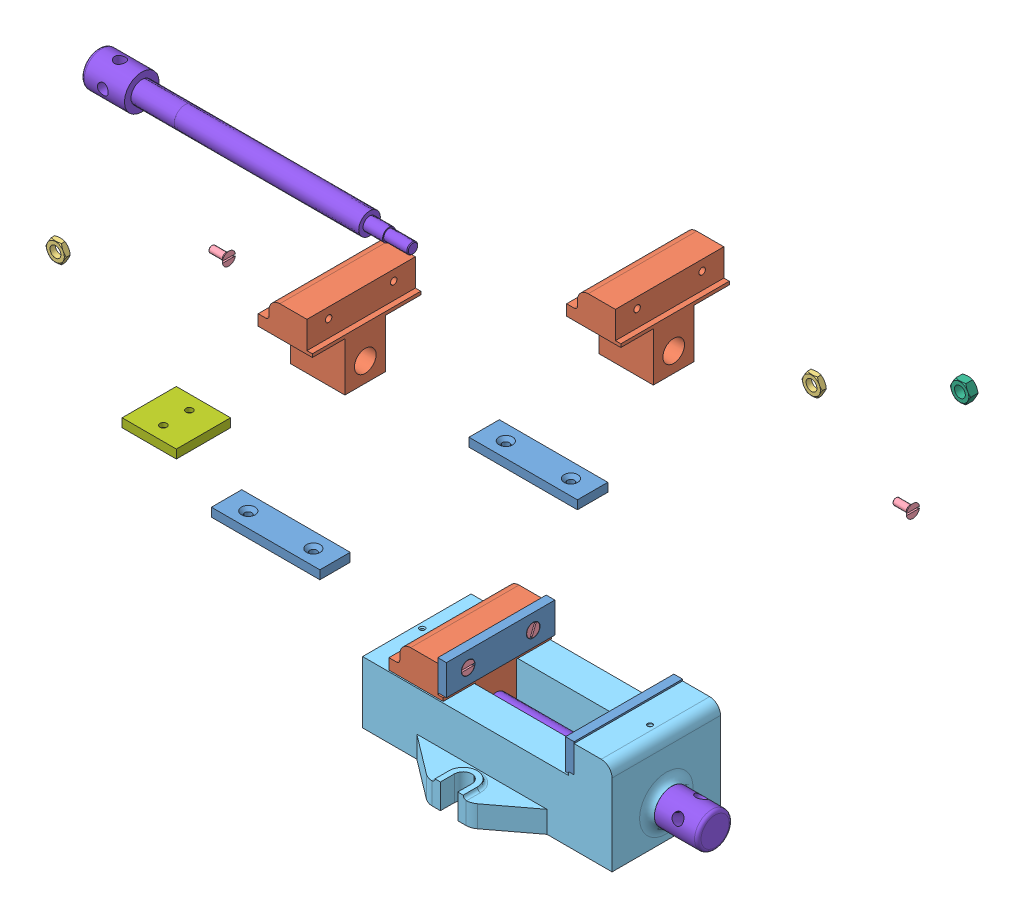
SolidWorks assembly Assem1, configuration Default. Lengths in mm.
Overall size (595.96 344.62 324.17).
26 component instances, 8 part files, 0 mates.
Components (placement in the parent):
- Grip-MV-1: Grip-MV [Default] at (31.9999 68.4692 65.7892) size (100 8 28)
- Jaw-MV-1: Jaw-MV [Default] at (-133.3209 133.664 48.2001) size (50 73 100)
- Lock NUt-MV-1: Lock NUt-MV [Default] at (173.2845 151.3233 -49.7428) size (18.72 17 5.02)
- M6-MV-1: M6-MV [Default] at (-179.2235 174.9323 146.2902) size (16 12 11.89)
- Grip-MV-2: Grip-MV [Default] at (-96.0011 3.3239 175.2518) size (100 8 28)
- Jaw-MV-2: Jaw-MV [Default] at (41.9223 174.6762 -60.9469) size (50 73 100)
- Lock NUt-MV-2: Lock NUt-MV [Default] at (-273.4654 159.6914 200.6034) size (18.72 17 5.02)
- M6-MV-2: M6-MV [Default] at (253.1151 90.412 -52.0541) size (16 12 11.89)
- MC-1: MC [Default] at (46.2829 -158.5516 -72.3603) size (293.02 89.5 160.55)
  - Body-MC-1: Body-MC [Default] at (30.956 63.4597 161.742) size (240 85 160.55)
  - Grip-MV-1: Grip-MV [Default] at (142.2604 135.9597 211.742) x (0 0 -1) z (0 1 0) size (100 8 28)
  - Jaw-MV-1: Jaw-MV [Default] at (-19.0508 117.8242 160.4986) size (50 73 100)
  - Lock NUt-MV-1: Lock NUt-MV [Default] at (-57.7396 93.4597 211.742) x (0 -0.991351 -0.131241) z (-1 0 0) size (18.72 17 5.02)
  - M6-MV-1: M6-MV [Default] at (140.6433 135.9597 241.742) x (-1 0 0) z (0 0.394964 -0.918697) size (16 12 11.89)
  - Nut-MV-1: Nut-MV [Default] at (-62.7396 93.4597 211.742) x (0 0 1) z (-1 0 0) size (18.72 17 8.02)
  - Plate-MV-1: Plate-MV [Default] at (-4.7063 67.4597 211.742) size (50 8 50)
  - Rod-MV-1: Rod-MV [Default] at (192.2758 93.4597 211.742) x (-1 0 0) z (0 -0.897027 0.441975) size (290 32 32)
  - M6-MV-2: M6-MV [Default] at (-4.7063 73.8426 199.742) x (0 -1 0) z (0.307872 0 -0.951428) size (16 12 11.89)
  - M6-MV-3: M6-MV [Default] at (-4.7063 73.8426 223.742) x (0 -1 0) z (-0.780901 0 -0.624654) size (16 12 11.89)
  - M6-MV-4: M6-MV [Default] at (140.6433 135.9597 181.742) x (-1 0 0) z (0 0.938965 0.344012) size (16 12 11.89)
  - Grip-MV-2: Grip-MV [Default] at (15.2937 138.9597 210.4986) x (0 0 -1) z (0 -1 0) size (100 8 28)
  - M6-MV-5: M6-MV [Default] at (16.9108 138.9597 180.4986) x (1 0 0) z (0 0.928772 -0.370652) size (16 12 11.89)
  - M6-MV-6: M6-MV [Default] at (16.9108 138.9597 240.4986) size (16 12 11.89)
- Nut-MV-1: Nut-MV [Default] at (258.3522 162.6831 -104.5123) size (18.72 17 8.02)
- Plate-MV-1: Plate-MV [Default] at (-193.0412 43.8605 174.5547) size (50 8 50)
- Rod-MV-1: Rod-MV [Default] at (-297.4315 233.5244 112.0265) size (290 32 32)
